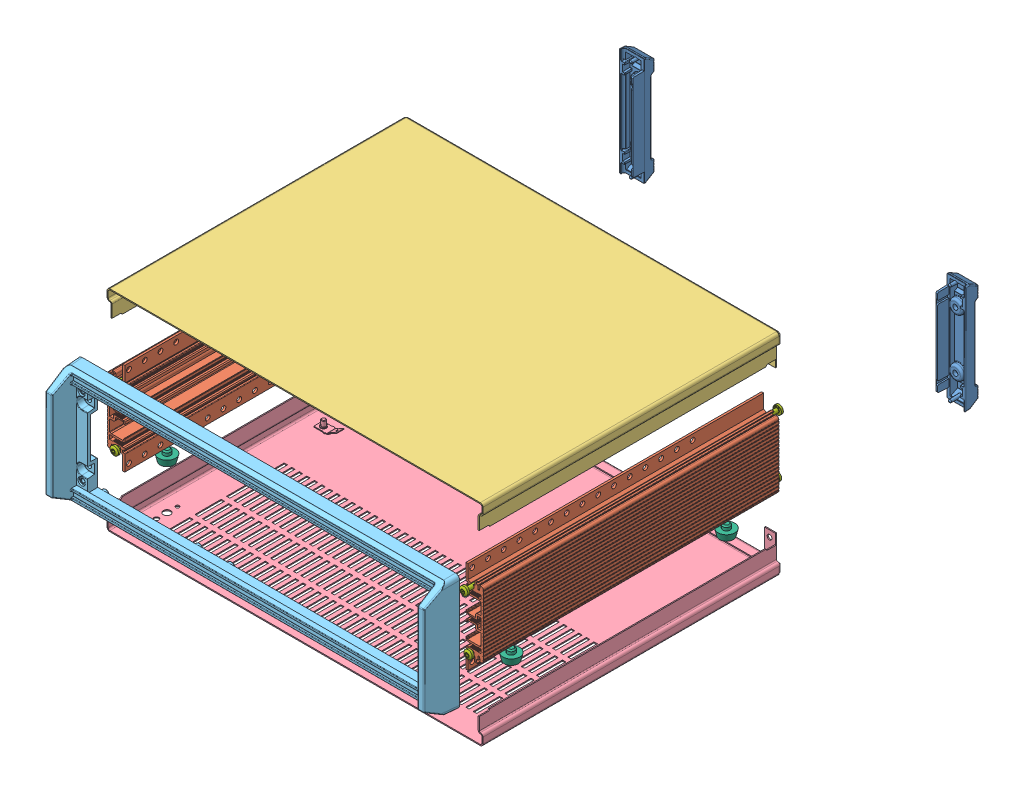
SolidWorks assembly 2UНеэкранированныйPropacProКорпус(14576-043), configuration По умолчанию. Lengths in mm.
Overall size (363.7 200.47 560.55).
19 component instances, 7 part files, 29 mates.
Components (placement in the parent):
- RUECKFUSS-2HE-vereinfacht-1: RUECKFUSS-2HE-vereinfacht [По умолчанию] at (-242.8073 110.2345 -582.1889) x (-0.000005 0 1) z (-1 0 -0.000005) size (20.51 103.44 20.8)
- RUECKFUSS-2HE-vereinfacht-2: RUECKFUSS-2HE-vereinfacht [По умолчанию] at (119.3926 65.673 -549.8491) x (0.000005 0 1) z (1 0 -0.000005) size (20.51 103.44 20.8)
- SEITENWAND-2HE-326T-1: SEITENWAND-2HE-326T [По умолчанию] at (102.9427 70.6787 -249.495) x (0 1 0) z (0 0 -1) size (88.1 16.5 281.6)
- SEITENWAND-2HE-326T-2: SEITENWAND-2HE-326T [По умолчанию] at (-226.3572 105.2287 -249.495) x (0 -1 0) z (0 0 -1) size (88.1 16.5 281.6)
- MANTEL-OB-----326T------63TE-1: MANTEL-OB-----326T------63TE [По умолчанию] at (-167.4939 188.0904 -287.7045) x (-1 0 0) z (0 -1 0) size (358.09 284.85 32)
- MANETL-UN-----326T------63TE-1: MANETL-UN-----326T------63TE [По умолчанию] at (43.4996 -12.3836 -287.7045) x (1 0 0) z (0 1 0) size (358.09 284.85 32)
- RAHMEN-2HE-63TE-1: RAHMEN-2HE-63TE [По умолчанию] at (-61.7073 87.9537 -41.261) x (1 0 0) z (0 0 1) size (363.7 111.05 35.05)
- 60224009_1-1: 60224009_1 [По умолчанию] at (-171.5723 108.4602 -120.4955) x (0.976576 0 -0.215173) z (0.215173 0 0.976576) size (16 11.2 16)
- 60224009_1-2: 60224009_1 [По умолчанию] at (-170.2659 108.4602 -313.495) size (16 11.2 16)
- 60224009_1-3: 60224009_1 [По умолчанию] at (157.8141 108.4602 -108.495) size (16 11.2 16)
- 60224009_1-4: 60224009_1 [По умолчанию] at (154.959 108.4602 -295.8793) x (0.948807 0 0.315857) z (-0.315857 0 0.948807) size (16 11.2 16)
- FLKOSHR-T-M-4-X16-_1-1: FLKOSHR-T-M-4-X16-_1 [По умолчанию] at (-230.0573 115.2037 -64.7324) x (0.882475 0.470359 0) z (0 0 1) size (8.2 9.29 19.12)
- FLKOSHR-T-M-4-X16-_1-2: FLKOSHR-T-M-4-X16-_1 [По умолчанию] at (-230.0573 60.7037 -66.002) x (0.738067 -0.674728 0) z (0 0 1) size (8.2 9.29 19.12)
- FLKOSHR-T-M-4-X16-_1-3: FLKOSHR-T-M-4-X16-_1 [По умолчанию] at (106.6427 115.2037 -62.2535) x (0.634987 0.772523 0) z (0 0 1) size (8.2 9.29 19.12)
- FLKOSHR-T-M-4-X16-_1-4: FLKOSHR-T-M-4-X16-_1 [По умолчанию] at (106.6427 60.7037 -66.4825) x (0.889291 0.457342 0) z (0 0 1) size (8.2 9.29 19.12)
- FLKOSHR-T-M-4-X16-_1-5: FLKOSHR-T-M-4-X16-_1 [По умолчанию] at (106.6427 60.7037 -353.6907) x (0.77074 -0.63715 0) z (0 0 -1) size (8.2 9.29 19.12)
- FLKOSHR-T-M-4-X16-_1-6: FLKOSHR-T-M-4-X16-_1 [По умолчанию] at (106.6427 115.2037 -355.3319) x (-0.572957 0.819585 0) z (0 0 -1) size (8.2 9.29 19.12)
- FLKOSHR-T-M-4-X16-_1-7: FLKOSHR-T-M-4-X16-_1 [По умолчанию] at (-230.0573 60.7037 -355.154) x (-0.949575 0.31354 0) z (0 0 -1) size (8.2 9.29 19.12)
- FLKOSHR-T-M-4-X16-_1-8: FLKOSHR-T-M-4-X16-_1 [По умолчанию] at (-230.0573 115.2037 -358.3518) x (0.999384 -0.035096 0) z (0 0 -1) size (8.2 9.29 19.12)
Mates (geometry in assembly coordinates):
- Совпадение1: coincident aligned: plane of 60224009_1-1 through (-229.0523 41.4929 -110.4213) normal (0 1 0); plane of 60224009_1-2 through (-228.5671 41.4929 -316.025) normal (0 1 0)
- Совпадение2: coincident aligned: plane of 60224009_1-2 through (-228.5671 41.4929 -316.025) normal (0 1 0); plane of 60224009_1-4 through (100.4415 41.4929 -316.6946) normal (0 1 0)
- Совпадение3: coincident aligned: plane of 60224009_1-3 through (99.5129 41.4929 -111.025) normal (0 1 0); plane of 60224009_1-4 through (100.4415 41.4929 -316.6946) normal (0 1 0)
- Концентричный2: concentric anti-aligned: circle of MANETL-UN-----326T------63TE-1; circle of 60224009_1-1
- Концентричный3: concentric anti-aligned: circle of MANETL-UN-----326T------63TE-1; circle of 60224009_1-3
- Концентричный4: concentric anti-aligned: circle of MANETL-UN-----326T------63TE-1; circle of 60224009_1-4
- Концентричный5: concentric anti-aligned: circle of MANETL-UN-----326T------63TE-1; circle of 60224009_1-2
- Совпадение4: coincident anti-aligned: plane of SEITENWAND-2HE-326T-1 through (112.5429 57.2037 -66.495) normal (1 0 0); plane of MANETL-UN-----326T------63TE-1 through (112.5429 -0.6836 -349.595) normal (-1 0 0)
- Совпадение5: coincident aligned: plane of SEITENWAND-2HE-326T-1 through (117.8555 42.7024 -66.495) normal (0 0 1); plane of MANETL-UN-----326T------63TE-1 through (-258.9411 12.2914 -66.495) normal (0 0 1)
- Совпадение8: coincident aligned: plane of SEITENWAND-2HE-326T-2 through (-241.27 133.205 -66.495) normal (0 0 1); plane of MANETL-UN-----326T------63TE-1 through (-258.9411 12.2914 -66.495) normal (0 0 1)
- Совпадение10: coincident aligned: plane of SEITENWAND-2HE-326T-1 through (117.8555 42.7024 -66.495) normal (0 0 1); plane of MANTEL-OB-----326T------63TE-1 through (134.9469 163.4154 -66.495) normal (0 0 1)
- Расстояние2: distance = 0 mm: plane of SEITENWAND-2HE-326T-1 through (112.5429 118.7038 -66.495) normal (1 0 0); point of MANTEL-OB-----326T------63TE-1
- Угол2: planar angle = 0 rad aligned: plane of MANTEL-OB-----326T------63TE-1 through (-238.4671 188.0904 -348.725) normal (0 1 0); plane of SEITENWAND-2HE-326T-1 through (100.8427 132.0038 -66.495) normal (0 1 0)
- Концентричный7: concentric anti-aligned: circle of SEITENWAND-2HE-326T-1; circle of FLKOSHR-T-M-4-X16-_1-6
- Концентричный8: concentric aligned: circle of SEITENWAND-2HE-326T-1; circle of FLKOSHR-T-M-4-X16-_1-5
- Концентричный9: concentric aligned: circle of SEITENWAND-2HE-326T-2; circle of FLKOSHR-T-M-4-X16-_1-8
- Концентричный10: concentric anti-aligned: circle of SEITENWAND-2HE-326T-2; circle of FLKOSHR-T-M-4-X16-_1-7
- Концентричный11: concentric anti-aligned: circle of SEITENWAND-2HE-326T-1; circle of FLKOSHR-T-M-4-X16-_1-3
- Концентричный12: concentric aligned: circle of SEITENWAND-2HE-326T-1; circle of FLKOSHR-T-M-4-X16-_1-4
- Концентричный13: concentric aligned: circle of SEITENWAND-2HE-326T-2; circle of FLKOSHR-T-M-4-X16-_1-1
- Концентричный14: concentric anti-aligned: circle of SEITENWAND-2HE-326T-2; circle of FLKOSHR-T-M-4-X16-_1-2
- Концентричный15: concentric aligned: circle of SEITENWAND-2HE-326T-1; circle of RAHMEN-2HE-63TE-1
- Концентричный16: concentric aligned: circle of SEITENWAND-2HE-326T-1; circle of RAHMEN-2HE-63TE-1
- Концентричный17: concentric aligned: circle of RAHMEN-2HE-63TE-1; circle of SEITENWAND-2HE-326T-2
- Концентричный18: concentric aligned: circle of RAHMEN-2HE-63TE-1; circle of SEITENWAND-2HE-326T-2
- Концентричный19: concentric aligned: cone of RUECKFUSS-2HE-vereinfacht-1 through (-230.0573 115.2037 -566.3008) axis (0 0 1); circle of SEITENWAND-2HE-326T-2
- Концентричный23: concentric anti-aligned: cone of RUECKFUSS-2HE-vereinfacht-2 through (106.6427 115.2037 -533.961) axis (0 0 1); circle of SEITENWAND-2HE-326T-1
- Перпендикулярность1: perpendicular: plane of RUECKFUSS-2HE-vereinfacht-1 through (-242.8072 132.7288 -568.3007) normal (0 -0.999391 -0.034899); plane of SEITENWAND-2HE-326T-2 through (-238.7573 95.1537 -66.495) normal (1 0 0)
- Перпендикулярность2: perpendicular: plane of RUECKFUSS-2HE-vereinfacht-2 through (119.3927 132.7288 -535.9608) normal (0 -0.999391 -0.034899); plane of SEITENWAND-2HE-326T-1 through (115.3427 80.7537 -66.495) normal (-1 0 0)
